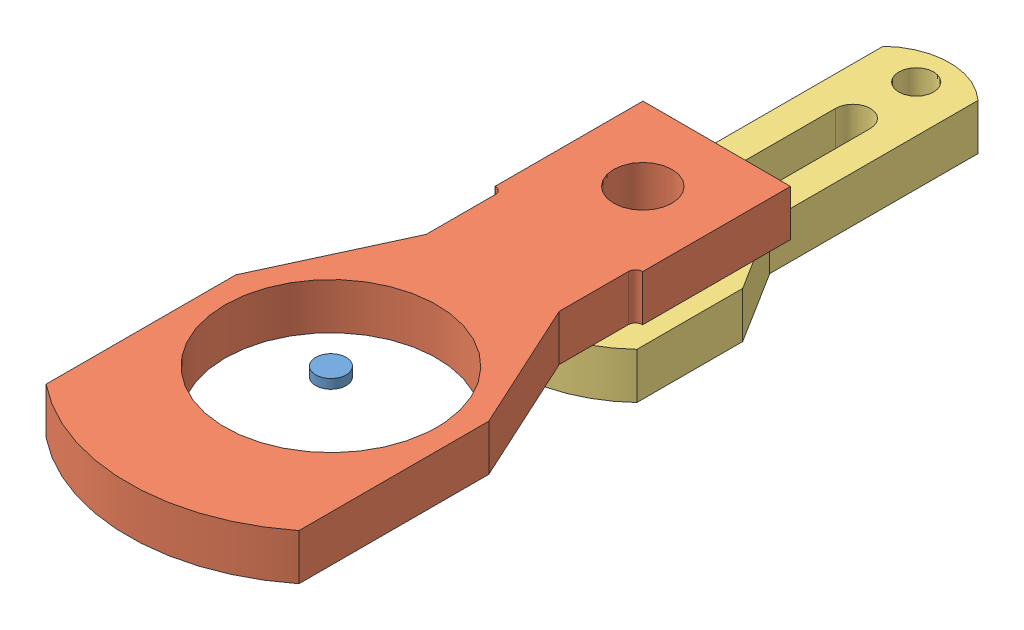
SolidWorks assembly Robot, configuration Predeterminado. Lengths in mm.
Overall size (275.41 100 891.12).
3 component instances, 3 part files, 4 mates.
Components (placement in the parent):
- Eje-3: Eje [Predeterminado] at (28.9881 17.9678 13.8124) size (33.02 10.16 33.02)
- Hombro-3: Hombro [Predeterminado] at (28.9881 17.9678 13.8124) x (0.000918 0 -1) z (0 -1 0) size (638.3 274.83 50)
- Brazo-4: Brazo [Predeterminado] at (29.2986 -32.0322 -324.3885) x (0.000918 0 -1) z (0 -1 0) size (478.79 200.15 50)
Mates (geometry in assembly coordinates):
- Coïncidente3: coincident: plane of Eje-3 through (28.9881 17.9678 13.8124) normal (0 1 0); plane of Hombro-3 through (109.101 17.9678 -236.5582) normal (0 1 0)
- Coaxiale1: concentric: cylinder of Eje-3 through (28.9881 7.8078 13.8124) axis (0 1 0) radius 16.51; cylinder of Hombro-3 through (28.9881 -32.0322 13.8124) axis (0 1 0) radius 115.062
- Coïncidente4: coincident: plane of Hombro-3 through (109.101 -32.0322 -236.5582) normal (0 -1 0); plane of Brazo-4 through (29.5358 -32.0322 -582.7064) normal (0 1 0)
- Coaxiale2: concentric: cylinder of Hombro-3 through (29.2986 -32.0322 -324.3885) axis (0 1 0) radius 31.75; cylinder of Brazo-4 through (29.2986 -82.0322 -324.3885) axis (0 1 0) radius 67.818
